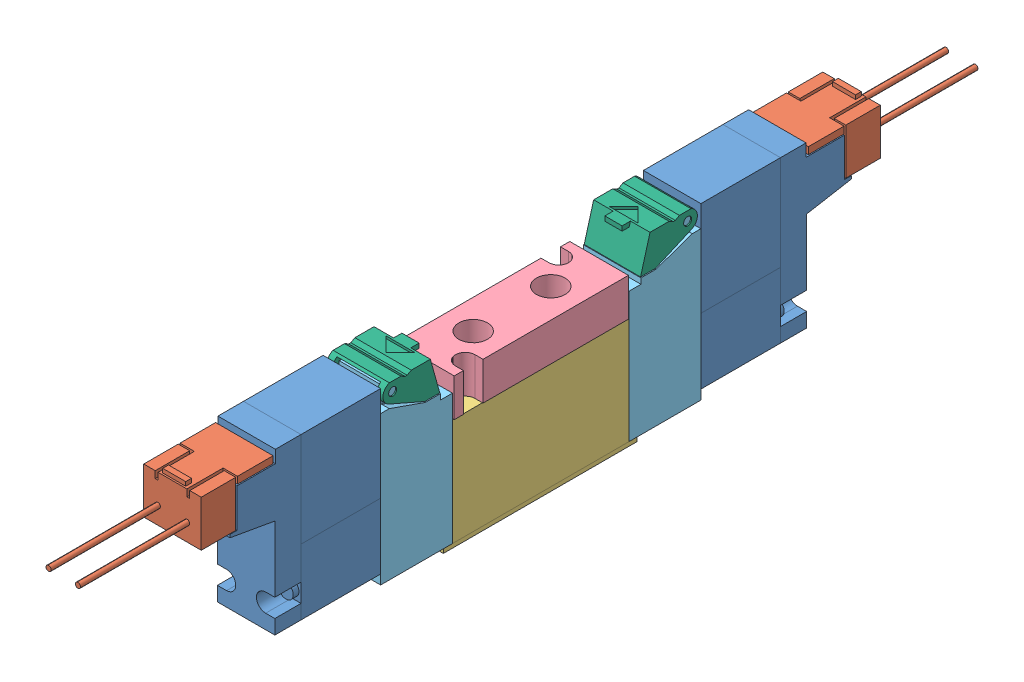
SolidWorks assembly 4GA129-M5-E01-4, configuration Default. Lengths in mm.
Overall size (10.2 30.4 156.1).
12 component instances, 6 part files, 0 mates.
Components (placement in the parent):
- 4GA129-M5-E01-4_D_100000_4G-Coil-SubASSY_01(EDC-E-H)-1: 4GA129-M5-E01-4_D_100000_4G-Coil-SubASSY_01(EDC-E-H) [Default] at (0 2.46 -27.85) size (10 27.94 50.2)
  - 4GA129-M5-E01-4_D_000102_4GcoilEDC_00(Default)-1: 4GA129-M5-E01-4_D_000102_4GcoilEDC_00(Default) [Default] at origin size (10 27.94 26.2)
  - 4GA129-M5-E01-4_D_000123_4GSocketAssyE_00(Default)-1: 4GA129-M5-E01-4_D_000123_4GSocketAssyE_00(Default) [Default] at (0 22.17 -25.2) size (10 8.7 31.5)
- 4GA129-M5-E01-4_D_100000_4G-Coil-SubASSY_01(EDC-E-H)-1-1: 4GA129-M5-E01-4_D_100000_4G-Coil-SubASSY_01(EDC-E-H)-1 [Default] at (0 2.46 27.85) x (-1 0 0) z (0 0 -1) size (10 27.94 50.2)
  - 4GA129-M5-E01-4_D_000102_4GcoilEDC_00(Default)-1: 4GA129-M5-E01-4_D_000102_4GcoilEDC_00(Default) [Default] at origin size (10 27.94 26.2)
  - 4GA129-M5-E01-4_D_000123_4GSocketAssyE_00(Default)-1: 4GA129-M5-E01-4_D_000123_4GSocketAssyE_00(Default) [Default] at (0 22.17 -25.2) size (10 8.7 31.5)
- 4GA129-M5-E01-4_D_000091_4G1Body_00(Default)-1: 4GA129-M5-E01-4_D_000091_4G1Body_00(Default) [Default] at origin size (10 19.4 33.7)
- 4GA129-M5-E01-4_D_000100_4G1PlateM5_00(Default)-1: 4GA129-M5-E01-4_D_000100_4G1PlateM5_00(Default) [Default] at (0 19.4 0) size (10.2 6.6 30.3)
- 4GA129-M5-E01-4_D_000097_4G1PistonAssy_00(Default)-1: 4GA129-M5-E01-4_D_000097_4G1PistonAssy_00(Default) [Default] at (0 0.8 -15.35) size (10 28.72 12.5)
- 4GA129-M5-E01-4_D_000097_4G1PistonAssy_00(Default)-2: 4GA129-M5-E01-4_D_000097_4G1PistonAssy_00(Default) [Default] at (0 0.8 15.35) x (-1 0 0) z (0 0 -1) size (10 28.72 12.5)
- 4GA129-M5-E01-4_D_000094_4G1ManualCover_00(Default)-1: 4GA129-M5-E01-4_D_000094_4G1ManualCover_00(Default) [Default] at (0 28.8 25.65) x (-1 0 0) z (0 0 -1) size (9.8 5.9 9.89)
- 4GA129-M5-E01-4_D_000094_4G1ManualCover_00(Default)-2: 4GA129-M5-E01-4_D_000094_4G1ManualCover_00(Default) [Default] at (0 28.8 -25.65) size (9.8 5.9 9.89)
